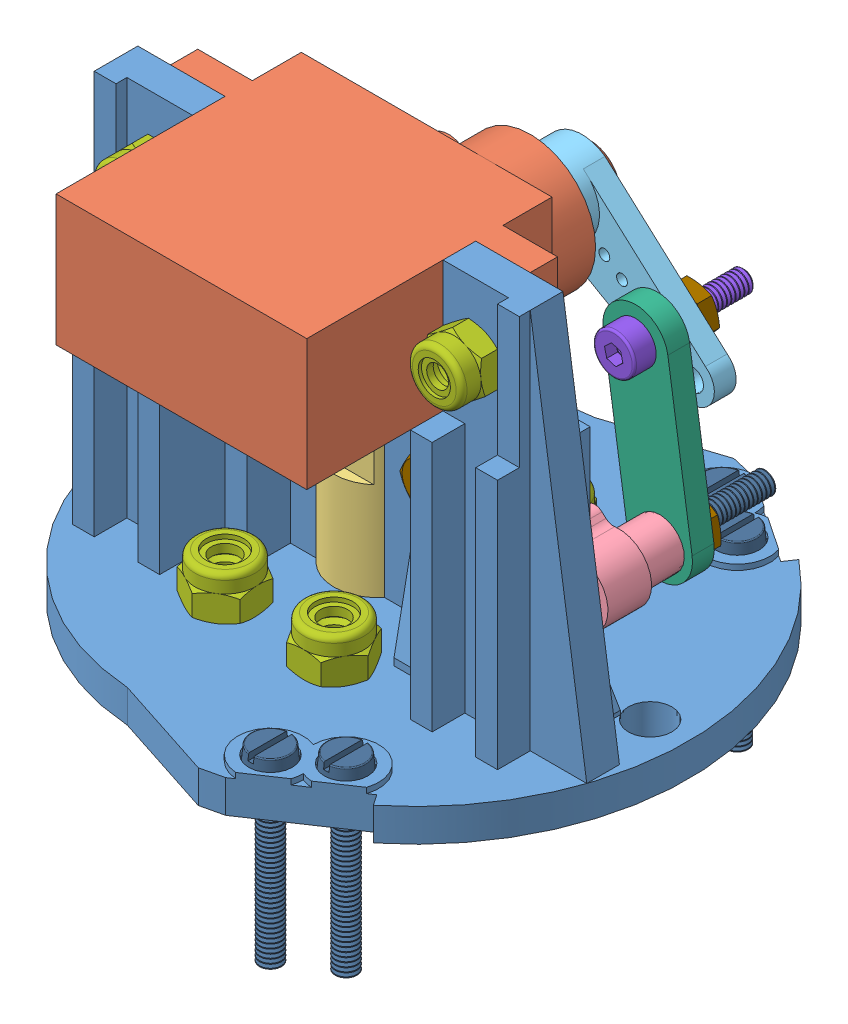
SolidWorks assembly Rückseite, configuration Standard. Lengths in mm.
Overall size (50 51 49.14).
25 component instances, 11 part files, 50 mates.
Components (placement in the parent):
- Backside-1: Backside [Standard] at (-0.7502 -6.4244 50) size (50 38 49.14)
- servo-1: servo [Standard] at (-9.7502 31.5756 70.5) x (1 0 0) z (0 1 0) size (33 29.25 12)
- Drücker-1: Drücker [Standard] at (-2.5879 13.5424 78.2478) x (1 0 0) z (0 0 -1) size (8 29 8)
- Hebel-1: Hebel [Standard] at (9.2498 10.5756 51) x (0.998913 -0.046622 0) z (0 0 -1) size (30.92 10.86 7.75)
- Servo-Arm-1: Servo-Arm [Standard] at (7.2498 25.5756 39.25) x (0.809748 -0.586777 0) z (-0.586777 -0.809748 0) size (20.6 4.3 7.2)
- Hebel2-1: Hebel2 [Standard] at (18.3863 4.2877 41.25) x (-0.148616 0.988895 0) z (0.988895 0.148616 0) size (21 2 6)
- User Library-Mutter DIN-985_-1: User Library-Mutter DIN-985_ [Mutter DIN-985 M3-A2] at (-4.7502 -3.4244 60) x (0 1 0) z (-0.455135 0 0.890422) size (4 6.35 5.5)
- User Library-Mutter DIN-985_-2: User Library-Mutter DIN-985_ [Mutter DIN-985 M3-A2] at (5.2498 -3.4244 60) x (0 1 0) z (-0.871788 0 0.489884) size (4 6.35 5.5)
- User Library-Mutter DIN-985_-3: User Library-Mutter DIN-985_ [Mutter DIN-985 M3-A2] at (5.2498 -3.4244 40) x (0 1 0) z (-0.77566 0 0.631152) size (4 6.35 5.5)
- User Library-Mutter DIN-985_-4: User Library-Mutter DIN-985_ [Mutter DIN-985 M3-A2] at (-4.7502 -3.4244 40) x (0 1 0) z (-0.229708 0 0.97326) size (4 6.35 5.5)
- socket head cap screw 4762_din-1: socket head cap screw 4762_din [ISO 4762 M2 x 10 --- 10S] at (9.2498 10.5756 43.8) x (0 0 1) z (0.035285 -0.999377 0) size (12 3.8 3.8)
- socket head cap screw 4762_din-2: socket head cap screw 4762_din [ISO 4762 M2 x 10 --- 10S] at (-0.7502 11.0424 55) x (0 0 -1) z (0.999211 -0.039713 0) size (12 3.8 3.8)
- socket head cap screw 4762_din-3: socket head cap screw 4762_din [ISO 4762 M2 x 10 --- 10S] at (16.157 19.1211 45.25) x (0 0 -1) z (-0.686907 0.726745 0) size (12 3.8 3.8)
- nut__style_1__m2x0_4__ansi_b18_2_4_1m-1: nut__style_1__m2x0_4__ansi_b18_2_4_1m [Default] at (-0.7502 11.0424 47) x (0.924405 -0.381413 0) z (0 0 -1) size (4.62 4 1.6)
- nut__style_1__m2x0_4__ansi_b18_2_4_1m-2: nut__style_1__m2x0_4__ansi_b18_2_4_1m [Default] at (16.157 19.1211 37.65) x (0.980747 -0.195284 0) z (0 0 1) size (4.62 4 1.6)
- nut__style_1__m2x0_4__ansi_b18_2_4_1m-3: nut__style_1__m2x0_4__ansi_b18_2_4_1m [Default] at (9.2498 10.5756 54.2) x (0.532315 -0.846547 0) z (0 0 1) size (4.62 4 1.6)
- User Library-Mutter DIN-985_-5: User Library-Mutter DIN-985_ [Mutter DIN-985 M2,5-A2] at (-12.7502 25.5756 58) x (0 0 1) z (0.965495 0.260421 0) size (3.8 5.77 5)
- User Library-Mutter DIN-985_-6: User Library-Mutter DIN-985_ [Mutter DIN-985 M2,5-A2] at (16.2498 25.5756 58) x (0 0 1) z (-0.395566 -0.918438 0) size (3.8 5.77 5)
- slotted cheese head screw_din-1: slotted cheese head screw_din [ISO 1207 - M2 x 16 --- 16S] at (10.151 -2.0244 70.7313) x (0 -1 0) z (0 0 1) size (17.4 3.8 3.8)
- slotted cheese head screw_din-2: slotted cheese head screw_din [ISO 1207 - M2 x 16 --- 16S] at (10.151 -2.0244 29.2687) x (0 -1 0) z (0 0 1) size (17.4 3.8 3.8)
- slotted cheese head screw_din-3: slotted cheese head screw_din [ISO 1207 - M2 x 16 --- 16S] at (14.3028 -2.0244 32.0549) x (0 -1 0) z (0 0 1) size (17.4 3.8 3.8)
- slotted cheese head screw_din-4: slotted cheese head screw_din [ISO 1207 - M2 x 16 --- 16S] at (14.3028 -2.0244 67.9451) x (0 -1 0) z (0 0 1) size (17.4 3.8 3.8)
- slotted cheese head screw_din-5: slotted cheese head screw_din [ISO 1207 - M2 x 16 --- 16S] at (18.3863 4.2877 50.85) x (0 0 -1) z (1 0 0) size (17.4 3.8 3.8)
- nut__style_1__m2x0_4__ansi_b18_2_4_1m-4: nut__style_1__m2x0_4__ansi_b18_2_4_1m [Default] at (18.3863 4.2877 41.25) x (0.924405 -0.381413 0) z (0 0 -1) size (4.62 4 1.6)
- cross fh tapping 7976_din-2: cross fh tapping 7976_din [Tapping screw DIN 7982-ST2.9x6.5-C-Z-S] at (7.2498 25.5756 38.5) x (0 0 1) z (-1 0 0) size (6.51 5.5 5.5)
Mates (geometry in assembly coordinates):
- Konzentrisch1: concentric anti-aligned: cylinder of Drücker-1 through (-0.7502 -15.4576 50) axis (0 1 0) radius 4; cylinder of Backside-1 through (-0.7502 -3.4244 50) axis (0 -1 0) radius 4
- Konzentrisch2: concentric aligned: cylinder of Backside-1 through (9.2498 10.5756 57.5) axis (0 0 1) radius 1.15; cylinder of Hebel-1 through (9.2498 10.5756 49) axis (0 0 1) radius 1.15
- Deckungsgleich1: coincident anti-aligned: plane of Hebel-1 through (9.2498 10.5756 49) normal (0 0 -1); plane of Backside-1 through (6.7498 13.5756 49) normal (0 0 1)
- Parallel1: parallel anti-aligned: plane of Drücker-1 through (-5.7502 5.5424 51) normal (0 0 -1); plane of Hebel-1 through (9.2498 10.5756 51) normal (0 0 1)
- Langloch1: slot anti-aligned: cylinder of Drücker-1 through (-0.7502 11.0424 54) axis (0 0 -1) radius 1; plane of Hebel-1 through (9.3034 11.7244 49) normal (-0.046622 -0.998913 0); cylinder of Hebel-1 through (-6.7328 11.3216 49) axis (0 0 1) radius 1.15
- Konzentrisch3: concentric anti-aligned: cylinder of servo-1 through (7.2498 25.5756 44) axis (0 0 1) radius 6; cylinder of Servo-Arm-1 through (7.2498 25.5756 43.55) axis (0 0 -1) radius 2.25
- Deckungsgleich6: coincident anti-aligned: plane of Backside-1 through (-9.7502 31.5756 58) normal (1 0 0); plane of servo-1 through (-9.7502 31.5756 48) normal (-1 0 0)
- Deckungsgleich7: coincident anti-aligned: plane of servo-1 through (18.2498 31.5756 55) normal (0 0 1); plane of Backside-1 through (-17.7502 19.5756 55) normal (0 0 -1)
- Deckungsgleich11: coincident aligned: plane of Backside-1 through (-0.7502 31.5756 50) normal (0 1 0); plane of servo-1 through (-9.7502 31.5756 48) normal (0 1 0)
- Deckungsgleich9: coincident anti-aligned: plane of Hebel2-1 through (18.3863 4.2877 41.25) normal (0 0 -1); plane of Servo-Arm-1 through (7.2498 25.5756 41.25) normal (0 0 1)
- Konzentrisch4: concentric anti-aligned: cylinder of Hebel-1 through (18.3863 4.2877 47) axis (0 0 1) radius 1.15; cylinder of Hebel2-1 through (18.3863 4.2877 43.25) axis (0 0 -1) radius 1.15
- Deckungsgleich12: coincident anti-aligned: plane of servo-1 through (7.2498 25.5756 41.25) normal (0 0 -1); plane of Servo-Arm-1 through (7.2498 25.5756 41.25) normal (0 0 1)
- Konzentrisch5: concentric aligned: cylinder of Servo-Arm-1 through (16.157 19.1211 41.25) axis (0 0 -1) radius 0.5; cylinder of Hebel2-1 through (16.157 19.1211 43.25) axis (0 0 -1) radius 1.15
- Deckungsgleich28: coincident anti-aligned: plane of Backside-1 through (-0.7502 -3.4244 50) normal (0 1 0); plane of User Library-Mutter DIN-985_-1 through (-7.1799 -3.4244 58.7581) normal (0 -1 0)
- Deckungsgleich29: coincident anti-aligned: plane of Backside-1 through (-0.7502 -3.4244 50) normal (0 1 0); plane of User Library-Mutter DIN-985_-2 through (3.9131 -3.4244 57.6211) normal (0 -1 0)
- Deckungsgleich31: coincident anti-aligned: plane of Backside-1 through (-0.7502 -3.4244 50) normal (0 1 0); plane of User Library-Mutter DIN-985_-3 through (3.5276 -3.4244 37.8834) normal (0 -1 0)
- Deckungsgleich30: coincident anti-aligned: plane of Backside-1 through (-0.7502 -3.4244 50) normal (0 1 0); plane of User Library-Mutter DIN-985_-4 through (-7.4059 -3.4244 39.3732) normal (0 -1 0)
- Deckungsgleich21: coincident anti-aligned: plane of Backside-1 through (9.2498 10.5756 45.8) normal (0 0 -1); plane of socket head cap screw 4762_din-1 through (7.351 10.5086 45.8) normal (0 0 1)
- Konzentrisch20: concentric anti-aligned: cylinder of Backside-1 through (9.2498 10.5756 57.5) axis (0 0 1) radius 1.15; cylinder of socket head cap screw 4762_din-1 through (9.2498 10.5756 12.05) axis (0 0 -1) radius 1
- Konzentrisch19: concentric anti-aligned: cylinder of Drücker-1 through (-0.7502 11.0424 54) axis (0 0 -1) radius 1; cylinder of socket head cap screw 4762_din-2 through (-0.7502 11.0424 86.75) axis (0 0 1) radius 1
- Deckungsgleich38: coincident anti-aligned: plane of Hebel2-1 through (18.3863 4.2877 43.25) normal (0 0 1); plane of socket head cap screw 4762_din-3 through (14.7762 17.816 43.25) normal (0 0 -1)
- Konzentrisch38: concentric anti-aligned: cylinder of Hebel2-1 through (16.157 19.1211 43.25) axis (0 0 -1) radius 1.15; cylinder of socket head cap screw 4762_din-3 through (16.157 19.1211 77) axis (0 0 1) radius 1
- Deckungsgleich41: coincident anti-aligned: plane of Drücker-1 through (4.2498 5.5424 47) normal (0 0 -1); plane of nut__style_1__m2x0_4__ansi_b18_2_4_1m-1 through (1.3852 10.1613 47) normal (0 0 1)
- Konzentrisch49: concentric aligned: circle of socket head cap screw 4762_din-2; circle of nut__style_1__m2x0_4__ansi_b18_2_4_1m-1
- Deckungsgleich39: coincident anti-aligned: plane of Servo-Arm-1 through (7.2498 25.5756 39.25) normal (0 0 -1); plane of nut__style_1__m2x0_4__ansi_b18_2_4_1m-2 through (18.4226 18.67 39.25) normal (0 0 1)
- Konzentrisch50: concentric anti-aligned: circle of socket head cap screw 4762_din-3; circle of nut__style_1__m2x0_4__ansi_b18_2_4_1m-2
- Deckungsgleich33: coincident anti-aligned: plane of Backside-1 through (9.2498 10.5756 54.2) normal (0 0 1); plane of nut__style_1__m2x0_4__ansi_b18_2_4_1m-3 through (10.4795 8.6201 54.2) normal (0 0 -1)
- Konzentrisch48: concentric aligned: circle of socket head cap screw 4762_din-1; circle of nut__style_1__m2x0_4__ansi_b18_2_4_1m-3
- Deckungsgleich36: coincident anti-aligned: plane of Backside-1 through (-11.7502 31.5756 58) normal (0 0 1); plane of User Library-Mutter DIN-985_-5 through (-12.1447 23.3307 58) normal (0 0 -1)
- Deckungsgleich37: coincident anti-aligned: plane of Backside-1 through (15.2498 31.5756 58) normal (0 0 1); plane of User Library-Mutter DIN-985_-6 through (14.1143 26.4954 58) normal (0 0 -1)
- Konzentrisch51: concentric aligned: circle of Backside-1; circle of User Library-Mutter DIN-985_-1
- Konzentrisch52: concentric aligned: circle of Backside-1; circle of User Library-Mutter DIN-985_-2
- Konzentrisch53: concentric aligned: circle of Backside-1; circle of User Library-Mutter DIN-985_-4
- Konzentrisch54: concentric aligned: circle of Backside-1; circle of User Library-Mutter DIN-985_-3
- Konzentrisch55: concentric aligned: circle of User Library-Mutter DIN-985_-5; cylinder of Backside-1 through (-12.7502 25.5756 41) axis (0 0 1) radius 1.25
- Konzentrisch56: concentric aligned: circle of User Library-Mutter DIN-985_-6; cylinder of Backside-1 through (16.2498 25.5756 41) axis (0 0 1) radius 1.25
- Deckungsgleich40: coincident anti-aligned: plane of Drücker-1 through (4.2498 5.5424 53) normal (0 0 1); plane of socket head cap screw 4762_din-2 through (-0.6747 12.9409 53) normal (0 0 -1)
- Konzentrisch59: concentric aligned: cylinder of Backside-1 through (14.3028 -13.4244 32.0549) axis (0 1 0) radius 1.1; cylinder of slotted cheese head screw_din-3 through (14.3028 23.3756 32.0549) axis (0 1 0) radius 1
- Konzentrisch60: concentric aligned: cylinder of Backside-1 through (10.151 -13.4244 29.2687) axis (0 1 0) radius 1.1; cylinder of slotted cheese head screw_din-2 through (10.151 23.3756 29.2687) axis (0 1 0) radius 1
- Konzentrisch61: concentric aligned: cylinder of Backside-1 through (14.3028 -13.4244 67.9451) axis (0 1 0) radius 1.1; cylinder of slotted cheese head screw_din-4 through (14.3028 23.3756 67.9451) axis (0 1 0) radius 1
- Konzentrisch62: concentric aligned: cylinder of Backside-1 through (10.151 -13.4244 70.7313) axis (0 1 0) radius 1.1; cylinder of slotted cheese head screw_din-1 through (10.151 23.3756 70.7313) axis (0 1 0) radius 1
- Deckungsgleich42: coincident anti-aligned: plane of Backside-1 through (-0.7502 -3.4244 50) normal (0 1 0); plane of slotted cheese head screw_din-3 through (15.3028 -3.4244 32.0549) normal (0 -1 0)
- Deckungsgleich43: coincident anti-aligned: plane of Backside-1 through (-0.7502 -3.4244 50) normal (0 1 0); plane of slotted cheese head screw_din-2 through (11.151 -3.4244 29.2687) normal (0 -1 0)
- Deckungsgleich44: coincident anti-aligned: plane of Backside-1 through (-0.7502 -3.4244 50) normal (0 1 0); plane of slotted cheese head screw_din-1 through (11.151 -3.4244 70.7313) normal (0 -1 0)
- Deckungsgleich45: coincident anti-aligned: plane of Backside-1 through (-0.7502 -3.4244 50) normal (0 1 0); plane of slotted cheese head screw_din-4 through (15.3028 -3.4244 67.9451) normal (0 -1 0)
- Konzentrisch64: concentric aligned: cylinder of Hebel-1 through (18.3863 4.2877 47) axis (0 0 1) radius 1.15; cylinder of slotted cheese head screw_din-5 through (18.3863 4.2877 76.25) axis (0 0 1) radius 1
- Deckungsgleich47: coincident aligned: circle of Hebel-1; plane of slotted cheese head screw_din-5 through (18.3863 5.2877 49.45) normal (0 0 -1)
- Deckungsgleich48: coincident anti-aligned: plane of Hebel2-1 through (18.3863 4.2877 41.25) normal (0 0 -1); plane of nut__style_1__m2x0_4__ansi_b18_2_4_1m-4 through (20.5217 3.4066 41.25) normal (0 0 1)
- Konzentrisch65: concentric anti-aligned: cylinder of Hebel2-1 through (18.3863 4.2877 43.25) axis (0 0 -1) radius 1.15; cylinder of nut__style_1__m2x0_4__ansi_b18_2_4_1m-4 through (18.3863 4.2877 41.25) axis (0 0 1) radius 0.7835
- Deckungsgleich50: coincident: circle of Servo-Arm-1; cone of cross fh tapping 7976_din-2 through (7.2498 25.5756 40.2) axis (0 0 1)
